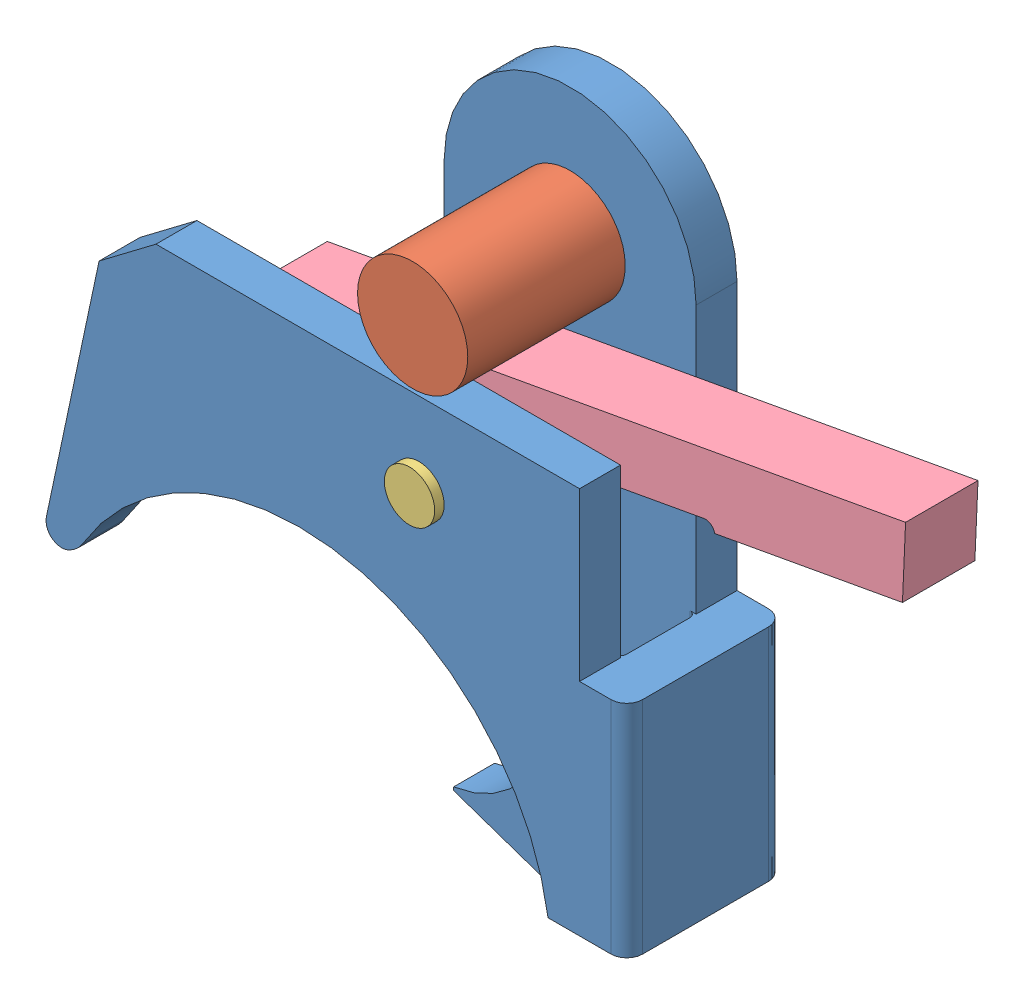
SolidWorks assembly Assemblage balancier, configuration Défaut. Lengths in mm.
Overall size (26.81 22.4 6.3).
4 component instances, 4 part files, 5 mates.
Components (placement in the parent):
- balancier-1: balancier [Défaut] at (7.9743 -8.167 1.2) size (18.44 22.4 5)
- axe balancier d 3.5-1: axe balancier d 3.5 [Défaut] at (2.4743 7.283 -2.5) size (3.5 3.5 6.3)
- axe balancier d 1.6-1: axe balancier d 1.6 [Défaut] at (1.3743 1.533 -2.5) size (1.6 1.6 5.3)
- levier balancier-1: levier balancier [Défaut] at (1.3743 1.533 1.1) x (0.983878 0.178842 0) z (0 0 -1) size (21 5.1 2.3)
Mates (geometry in assembly coordinates):
- Coïncidente1: coincident aligned: plane of balancier-1 through (7.9743 -8.167 -2.5) normal (0 0 -1); plane of axe balancier d 3.5-1 through (2.4743 7.283 -2.5) normal (0 0 -1)
- Coaxiale1: concentric aligned: cylinder of balancier-1 through (2.4743 7.283 -1.2) axis (0 0 -1) radius 1.75; cylinder of axe balancier d 3.5-1 through (2.4743 7.283 3.8) axis (0 0 -1) radius 1.75
- Coaxiale6: concentric anti-aligned: cylinder of axe balancier d 1.6-1 through (1.3743 1.533 2.8) axis (0 0 -1) radius 0.8; cylinder of levier balancier-1 through (1.3743 1.533 -1.2) axis (0 0 1) radius 0.8
- Coïncidente10: coincident anti-aligned: plane of balancier-1 through (-1.7372 -6.3535 -1.2) normal (0 0 1); plane of levier balancier-1 through (-1.3736 1.6404 -1.2) normal (0 0 -1)
- Coaxiale7: concentric aligned: cylinder of balancier-1 through (1.3743 1.533 2.5) axis (0 0 -1) radius 0.8; cylinder of axe balancier d 1.6-1 through (1.3743 1.533 2.8) axis (0 0 -1) radius 0.8
